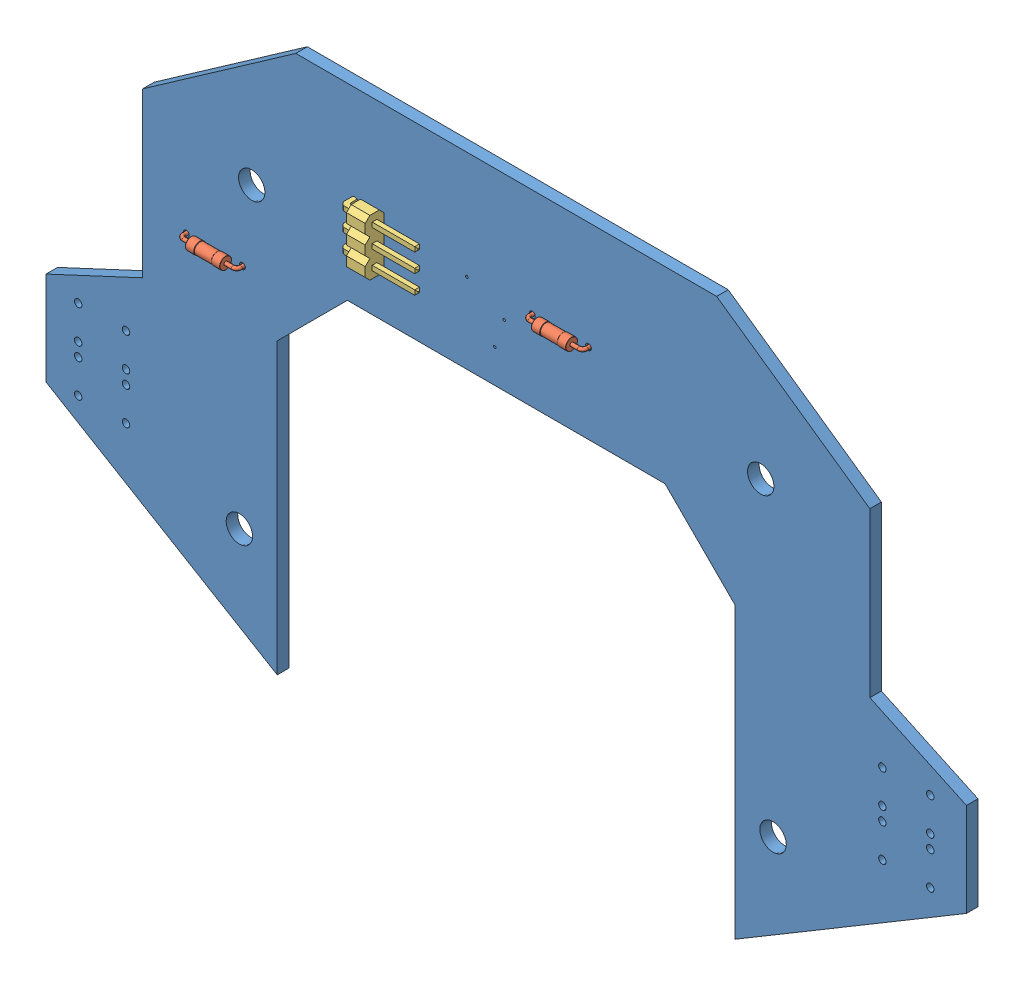
SolidWorks assembly backside_pcb_new_sol, configuration Default. Lengths in mm.
Overall size (125 74.35 5.54).
5 component instances, 3 part files, 0 mates.
Components (placement in the parent):
- PCB Component_1-1: PCB Component_1 [Default] at origin size (125 74.35 5.54)
  - Board_11-1: Board_11 [Default] at origin size (125 74.35 1.57)
  - 0204-7_R11-1: 0204-7_R11 [Default] at (69.85 59.69 1.57) x (-1 0 0) z (0 0 1) size (8.2 1.6 3.52)
  - 0204-7_R11-2: 0204-7_R11 [Default] at (22.86 45.72 1.57) size (8.2 1.6 3.52)
  - 1X03-90_JP2-1: 1X03-90_JP2 [Default] at (45.72 58.42 1.57) x (0 -1 0) z (0 0 1) size (7.62 10.36 5.54)
